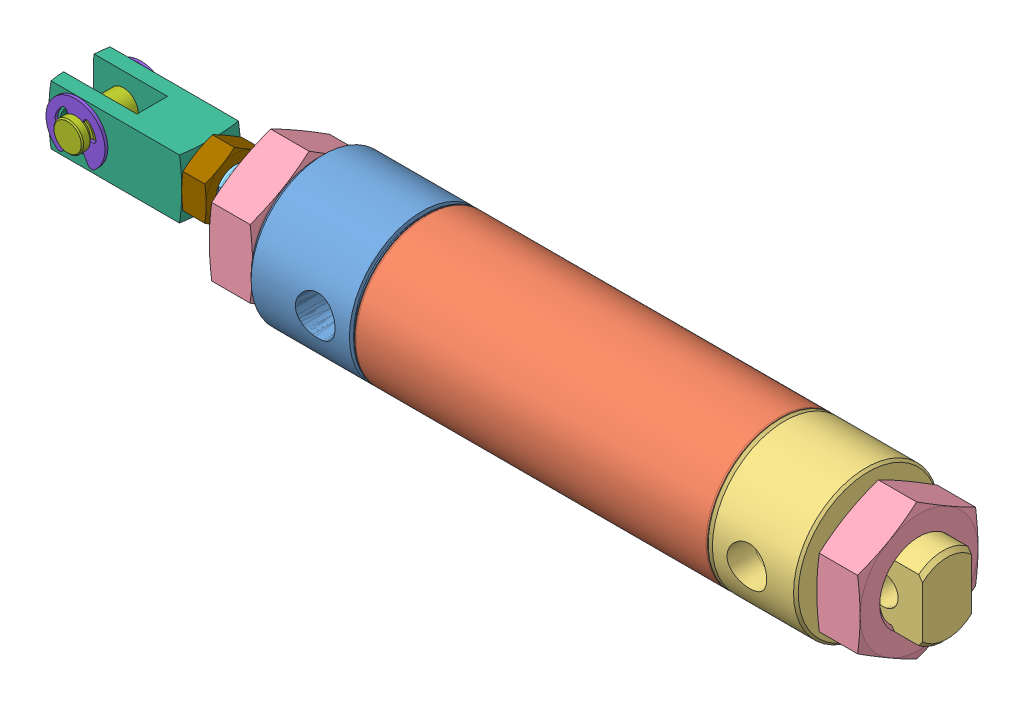
SolidWorks assembly Assem3, configuration Default. Lengths in mm.
Overall size (281.55 46.85 46.85).
13 component instances, 11 part files, 31 mates.
Components (placement in the parent):
- 242_8-DPC(F,D-231-3)0000_0_dummy-1: 242_8-DPC(F,D-231-3)0000_0_dummy [Default] at origin
- 24R000-0_rod_guide-1: 24R000-0_rod_guide [Default] at origin size (60.32 46.85 46.85)
- 24R-4_53350C-1: 24R-4_53350C [Default] at (53.3908 0 0) size (117.06 46.85 46.85)
- 24P0000_rear_head-1: 24P0000_rear_head [Default] at (161.671 0 0) size (60.32 46.85 46.85)
- D-1331-1: D-1331 [Default] at (198.9582 0 0) x (0 0 -1) z (-1 0 0) size (38.1 43.99 13.97)
- D-1331-2: D-1331 [Default] at (16.6624 0 0) x (0 0 -1) z (1 0 0) size (38.1 43.99 13.97)
- C-242_8-DP0_rod-1: C-242_8-DP0_rod [Default] at origin size (191.9 44.69 44.69)
- D-231-3-dummy-1: D-231-3-dummy [Default] at (-49.022 0 0)
- D-14041-1: D-14041 [Default] at (-49.022 0 0) x (1 0 0) z (0 0 -1) size (44.68 19.05 19.05)
- D-8383-1: D-8383 [Default] at (-49.022 0 0) x (0 0 1) z (-1 0 0) size (26.19 9.56 9.56)
- D-5867-1: D-5867 [Default] at (-49.022 0 10.1029) x (-1 0 0) z (0 0 -1) size (19.05 17.19 0.93)
- D-5867-2: D-5867 [Default] at (-49.022 0 -10.1029) x (-1 0 0) z (0 0 -1) size (19.05 17.19 0.93)
- D-98-1: D-98 [Default] at (-15.748 0 0) x (0 0 1) z (-1 0 0) size (19.05 22 7.87)
Mates (geometry in assembly coordinates):
- Distance2: distance = 0 mm aligned: plane of 24R000-0_rod_guide-1 through (0 0 0) normal (1 0 0); plane of 242_8-DPC(F,D-231-3)0000_0_dummy-1 through (0 0 0) normal (1 0 0)
- Coincident1: coincident aligned: line of 242_8-DPC(F,D-231-3)0000_0_dummy-1 through (80.9 0 0) axis (-1 0 0); line of 24R000-0_rod_guide-1 through (80.9 0 0) axis (-1 0 0)
- Angle3: planar angle = 0 rad aligned: plane of 24R000-0_rod_guide-1 through (0 0 0) normal (0 0 -1); plane of 242_8-DPC(F,D-231-3)0000_0_dummy-1 through (0 0 0) normal (0 0 -1)
- Distance4: distance = 0 mm aligned: plane of 24R-4_53350C-1 through (53.3908 0 0) normal (1 0 0); plane of 24R000-0_rod_guide-1 through (53.3908 0 0) normal (1 0 0)
- Coincident2: coincident aligned: line of 24R000-0_rod_guide-1 through (80.9 0 0) axis (-1 0 0); line of 24R-4_53350C-1 through (134.2908 0 0) axis (-1 0 0)
- Angle6: planar angle = 0 rad aligned: plane of 24R-4_53350C-1 through (53.3908 0 0) normal (0 0 -1); plane of 24R000-0_rod_guide-1 through (0 0 0) normal (0 0 -1)
- Distance6: distance = 0 mm aligned: plane of 24P0000_rear_head-1 through (168.5417 0 0) normal (1 0 0); plane of 24R-4_53350C-1 through (168.5417 0 0) normal (1 0 0)
- Coincident3: coincident aligned: line of 24R-4_53350C-1 through (134.2908 0 0) axis (-1 0 0); line of 24P0000_rear_head-1 through (242.571 0 0) axis (-1 0 0)
- Angle9: planar angle = 2 rad aligned: plane of 24P0000_rear_head-1 through (161.671 0 0) normal (0 0 -1); plane of 24R-4_53350C-1 through (53.3908 0 0) normal (0 0 -1)
- Distance7: distance = 0 mm anti-aligned: plane of D-1331-1 through (198.9582 0 0) normal (-1 0 0); plane of 24P0000_rear_head-1 through (198.9582 0 0) normal (1 0 0)
- Coincident4: coincident anti-aligned: line of 24P0000_rear_head-1 through (242.571 0 0) axis (-1 0 0); line of D-1331-1 through (118.0582 0 0) axis (1 0 0)
- Angle12: planar angle = 0 rad aligned: plane of D-1331-1; plane of 24P0000_rear_head-1 through (161.671 0 0) normal (0 0 -1)
- Distance9: distance = 0 mm aligned: plane of D-1331-2 through (16.6624 0 0) normal (1 0 0); plane of 24R000-0_rod_guide-1 through (16.6624 0 0) normal (1 0 0)
- Coincident5: coincident aligned: line of 24R000-0_rod_guide-1 through (80.9 0 0) axis (-1 0 0); line of D-1331-2 through (97.5624 0 0) axis (-1 0 0)
- Angle15: planar angle = 0 rad aligned: plane of D-1331-2 through (16.6624 0 0) normal (0 0 -1); plane of 24R000-0_rod_guide-1 through (0 0 0) normal (0 0 -1)
- LimitDistance2: limit distance = 0 mm aligned: plane of C-242_8-DP0_rod-1 through (0 0 0) normal (1 0 0); plane of 24R000-0_rod_guide-1 through (0 0 0) normal (1 0 0)
- Coincident6: coincident aligned: line of 24R000-0_rod_guide-1 through (80.9 0 0) axis (-1 0 0); line of C-242_8-DP0_rod-1 through (80.9 0 0) axis (-1 0 0)
- Distance11: distance = 0 mm aligned: plane of D-231-3-dummy-1 through (-34.798 0 0) normal (1 0 0); plane of C-242_8-DP0_rod-1 through (-34.798 0 0) normal (1 0 0)
- Coincident7: coincident aligned: line of C-242_8-DP0_rod-1 through (80.9 0 0) axis (-1 0 0); line of D-231-3-dummy-1 through (31.878 0 0) axis (-1 0 0)
- Angle18: planar angle = 0 rad aligned: plane of D-231-3-dummy-1 through (-49.022 0 0) normal (0 0 -1); plane of C-242_8-DP0_rod-1 through (0 0 0) normal (0 0 -1)
- Distance12: distance = 0 mm anti-aligned: plane of D-14041-1 through (-49.022 0 0) normal (0 0 -1); plane of D-231-3-dummy-1 through (-49.022 0 0) normal (0 0 1)
- Coincident8: coincident anti-aligned: line of D-231-3-dummy-1 through (-49.022 0 80.9) axis (0 0 -1); line of D-14041-1 through (-49.022 0 -80.9) axis (0 0 1)
- Angle21: planar angle = 0 rad aligned: plane of D-14041-1; plane of D-231-3-dummy-1 through (-49.022 0 0) normal (1 0 0)
- Coincident9: coincident anti-aligned: plane of D-14041-1 through (-49.022 0 0) normal (0 0 -1); plane of D-8383-1 through (-49.022 0 0) normal (0 0 1)
- Coincident10: coincident anti-aligned: line of D-14041-1 through (-49.022 0 -80.9) axis (0 0 1); line of D-8383-1 through (-49.022 0 80.9) axis (0 0 -1)
- Coincident11: coincident anti-aligned: plane of D-8383-1 through (-49.022 0 10.1029) normal (0 0 1); plane of D-5867-1 through (-49.022 0 10.1029) normal (0 0 -1)
- Coincident12: coincident anti-aligned: line of D-8383-1 through (-49.022 0 80.9) axis (0 0 -1); line of D-5867-1 through (-49.022 0 -70.7972) axis (0 0 1)
- Coincident13: coincident anti-aligned: plane of D-8383-1 through (-49.022 0 -10.1029) normal (0 0 1); plane of D-5867-2 through (-49.022 0 -10.1029) normal (0 0 -1)
- Coincident14: coincident anti-aligned: line of D-8383-1 through (-49.022 0 80.9) axis (0 0 -1); line of D-5867-2 through (-49.022 0 -91.0028) axis (0 0 1)
- Coincident15: coincident anti-aligned: plane of D-14041-1; plane of D-98-1 through (-15.748 0 0) normal (-1 0 0)
- Coincident16: coincident anti-aligned: line of D-14041-1 through (31.878 0 0) axis (-1 0 0); line of D-98-1 through (-96.648 0 0) axis (1 0 0)
